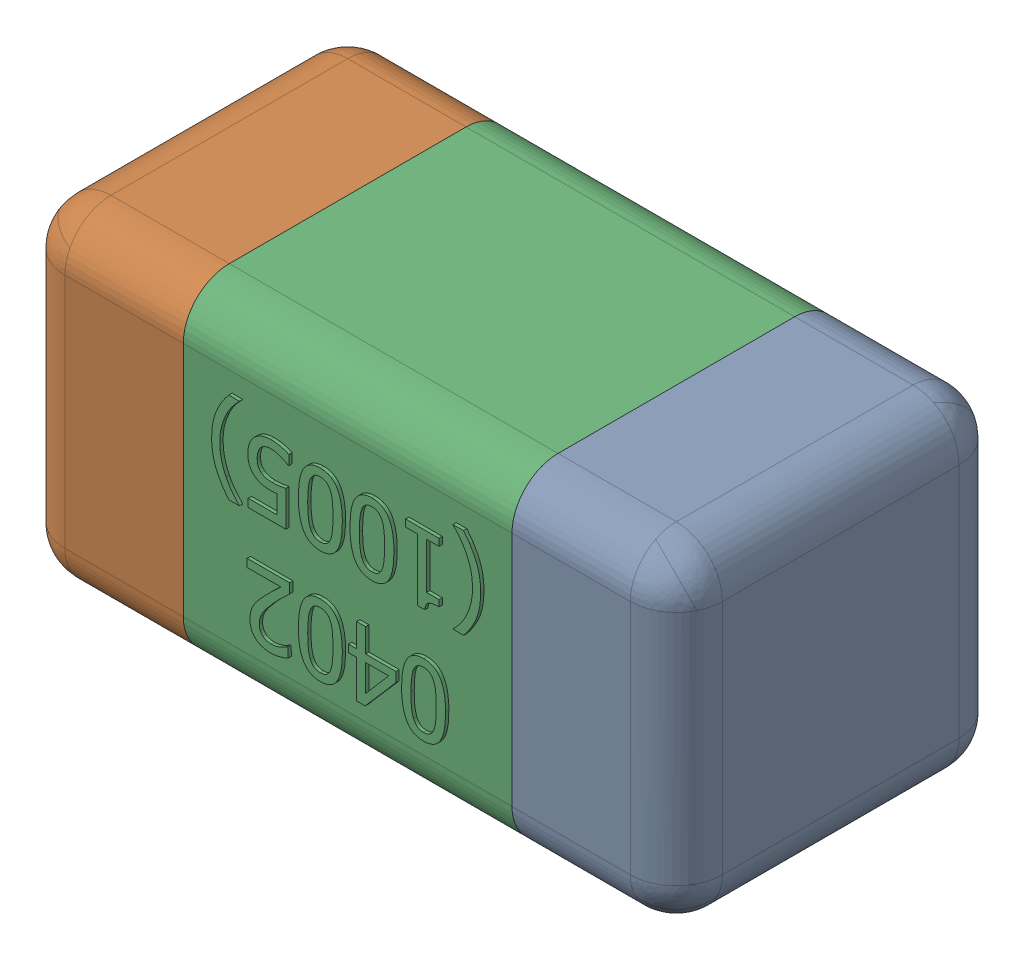
SolidWorks assembly C8, configuration Standard. Lengths in mm.
Overall size (1.01 0.51 0.51).
4 component instances, 3 part files, 0 mates.
Components (placement in the parent):
- C8-subassembly-1-1: C8-subassembly-1 [Standard] at (5.8999 3.7 0) x (-1 0 0) z (0 0 1) size (1.01 0.51 0.51)
  - User Library-0402_Cap-1: User Library-0402_Cap [Standard] at origin size (0.26 0.51 0.51)
  - User Library-0402_Cap-1-1: User Library-0402_Cap-1 [Standard] at origin size (0.26 0.5 0.51)
  - User Library-0402_Cap-2-1: User Library-0402_Cap-2 [Standard] at origin size (0.5 0.5 0.51)
